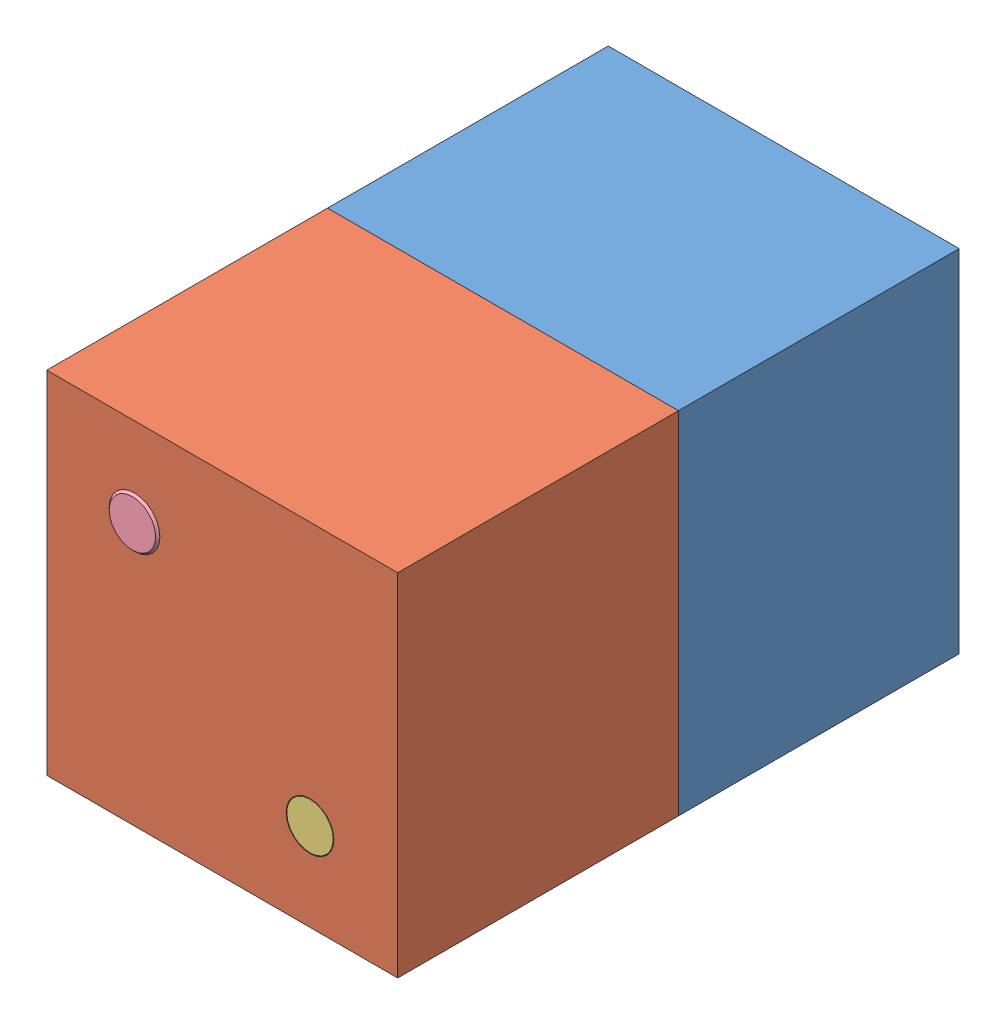
SolidWorks assembly Assemblage1, configuration Défaut. Lengths in mm.
Overall size (105 50 136.8).
4 component instances, 4 part files, 6 mates.
Components (placement in the parent):
- Pièce1 perçage-1: Pièce1 perçage [Défaut] at (23.0036 -24.2347 50) size (50 50 40)
- Pièce2 perçage-1: Pièce2 perçage [Défaut] at (-26.9964 25.7653 130) x (0 1 0) z (0 0 -1) size (50 50 40)
- socket countersunk head screw_iso-4: socket countersunk head screw_iso [ISO 10642 - M8 x 80 - 28N] at (10.5036 -11.7347 50) x (0 0 1) z (-0.84822 -0.529645 0) size (80 15.24 15.24)
- socket head cap screw_iso-4: socket head cap screw_iso [ISO 4762 M8 x 70 - 28N] at (-14.4964 13.2653 52.3039) x (0 0 1) z (-1 0 0) size (78 13 13)
Mates (geometry in assembly coordinates):
- Coaxiale1: concentric aligned: cylinder of Pièce1 perçage-1 through (10.5036 -11.7347 50) axis (0 0 -1) radius 4.5; cylinder of Pièce2 perçage-1 through (10.5036 -11.7347 90) axis (0 0 -1) radius 3.4
- Coaxiale3: concentric aligned: cylinder of Pièce1 perçage-1 through (-14.4964 13.2653 50) axis (0 0 -1) radius 4.5; cylinder of Pièce2 perçage-1 through (-14.4964 13.2653 90) axis (0 0 -1) radius 3.4
- Coïncidente2: coincident anti-aligned: plane of Pièce1 perçage-1 through (23.0036 -24.2347 90) normal (0 0 1); plane of Pièce2 perçage-1 through (-26.9964 25.7653 90) normal (0 0 -1)
- Coaxiale6: concentric aligned: cylinder of Pièce1 perçage-1 through (10.5036 -11.7347 50) axis (0 0 -1) radius 4.5; cylinder of socket countersunk head screw_iso-4 through (10.5036 -11.7347 50) axis (0 0 -1) radius 4
- Coïncidente4: coincident aligned: plane of Pièce1 perçage-1 through (23.0036 -24.2347 50) normal (0 0 -1); plane of socket countersunk head screw_iso-4 through (10.5036 -11.7347 50) normal (0 0 -1)
- Coaxiale8: concentric aligned: cylinder of Pièce1 perçage-1 through (-14.4964 13.2653 50) axis (0 0 -1) radius 4.5; cylinder of socket head cap screw_iso-4 through (-14.4964 13.2653 20.5539) axis (0 0 -1) radius 6.5
